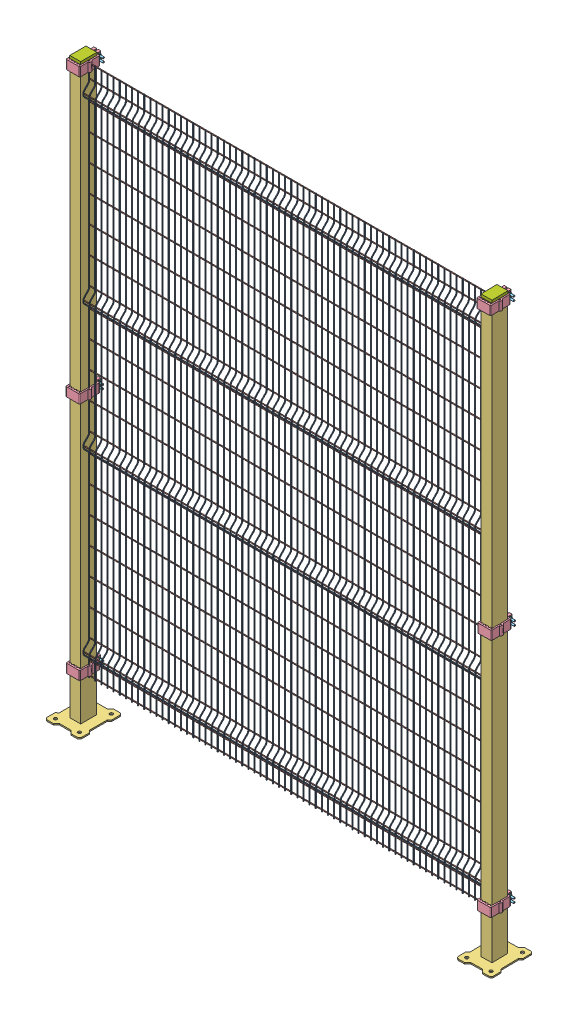
SolidWorks assembly conjunto malha 20x100, configuration Valor predeterminado. Lengths in mm.
Overall size (1674.09 2165.88 162.39).
151 component instances, 7 part files, 62 mates.
Components (placement in the parent):
- Painel Lync Pro 1500 x 2000 step-1: Painel Lync Pro 1500 x 2000 step [Valor predeterminado] at (1050.3689 171.7839 2000) size (1500 2000 28)
  - Painel Lync Pro 1500 x 2000 step.STEP-1: Painel Lync Pro 1500 x 2000 step.STEP [Valor predeterminado] at origin size (1500 2000 28)
    - Arame vertical.STEP-1: Arame vertical.STEP [Valor predeterminado] at (-259.8823 -1220.0686 1996) size (3 2000 25)
    - Arame vertical.STEP-2: Arame vertical.STEP [Valor predeterminado] at (-282.8823 -1220.0686 1996) size (3 2000 25)
    - Arame vertical.STEP-3: Arame vertical.STEP [Valor predeterminado] at (-305.8823 -1220.0686 1996) size (3 2000 25)
    - Arame vertical.STEP-4: Arame vertical.STEP [Valor predeterminado] at (-328.8823 -1220.0686 1996) size (3 2000 25)
    - Arame vertical.STEP-5: Arame vertical.STEP [Valor predeterminado] at (-351.8823 -1220.0686 1996) size (3 2000 25)
    - Arame vertical.STEP-6: Arame vertical.STEP [Valor predeterminado] at (-374.8823 -1220.0686 1996) size (3 2000 25)
    - Arame vertical.STEP-7: Arame vertical.STEP [Valor predeterminado] at (-397.8823 -1220.0686 1996) size (3 2000 25)
    - Arame vertical.STEP-8: Arame vertical.STEP [Valor predeterminado] at (-420.8823 -1220.0686 1996) size (3 2000 25)
    - Arame vertical.STEP-9: Arame vertical.STEP [Valor predeterminado] at (-443.8823 -1220.0686 1996) size (3 2000 25)
    - Arame vertical.STEP-10: Arame vertical.STEP [Valor predeterminado] at (-466.8823 -1220.0686 1996) size (3 2000 25)
    - Arame vertical.STEP-11: Arame vertical.STEP [Valor predeterminado] at (-489.8823 -1220.0686 1996) size (3 2000 25)
    - Arame vertical.STEP-12: Arame vertical.STEP [Valor predeterminado] at (-512.8823 -1220.0686 1996) size (3 2000 25)
    - Arame vertical.STEP-13: Arame vertical.STEP [Valor predeterminado] at (-535.8823 -1220.0686 1996) size (3 2000 25)
    - Arame vertical.STEP-14: Arame vertical.STEP [Valor predeterminado] at (-558.8823 -1220.0686 1996) size (3 2000 25)
    - Arame vertical.STEP-15: Arame vertical.STEP [Valor predeterminado] at (-581.8823 -1220.0686 1996) size (3 2000 25)
    - Arame vertical.STEP-16: Arame vertical.STEP [Valor predeterminado] at (-604.8823 -1220.0686 1996) size (3 2000 25)
    - Arame vertical.STEP-17: Arame vertical.STEP [Valor predeterminado] at (-627.8823 -1220.0686 1996) size (3 2000 25)
    - Arame vertical.STEP-18: Arame vertical.STEP [Valor predeterminado] at (-650.8823 -1220.0686 1996) size (3 2000 25)
    - Arame vertical.STEP-19: Arame vertical.STEP [Valor predeterminado] at (-673.8823 -1220.0686 1996) size (3 2000 25)
    - Arame vertical.STEP-20: Arame vertical.STEP [Valor predeterminado] at (-696.8823 -1220.0686 1996) size (3 2000 25)
    - Arame vertical.STEP-21: Arame vertical.STEP [Valor predeterminado] at (-719.8823 -1220.0686 1996) size (3 2000 25)
    - Arame vertical.STEP-22: Arame vertical.STEP [Valor predeterminado] at (-742.8823 -1220.0686 1996) size (3 2000 25)
    - Arame vertical.STEP-23: Arame vertical.STEP [Valor predeterminado] at (-765.8823 -1220.0686 1996) size (3 2000 25)
    - Arame vertical.STEP-24: Arame vertical.STEP [Valor predeterminado] at (-788.8823 -1220.0686 1996) size (3 2000 25)
    - Arame vertical.STEP-25: Arame vertical.STEP [Valor predeterminado] at (-811.8823 -1220.0686 1996) size (3 2000 25)
    - Arame vertical.STEP-26: Arame vertical.STEP [Valor predeterminado] at (-834.8823 -1220.0686 1996) size (3 2000 25)
    - Arame vertical.STEP-27: Arame vertical.STEP [Valor predeterminado] at (-857.8823 -1220.0686 1996) size (3 2000 25)
    - Arame vertical.STEP-28: Arame vertical.STEP [Valor predeterminado] at (-880.8823 -1220.0686 1996) size (3 2000 25)
    - Arame vertical.STEP-29: Arame vertical.STEP [Valor predeterminado] at (-903.8823 -1220.0686 1996) size (3 2000 25)
    - Arame vertical.STEP-30: Arame vertical.STEP [Valor predeterminado] at (-926.8823 -1220.0686 1996) size (3 2000 25)
    - Arame vertical.STEP-31: Arame vertical.STEP [Valor predeterminado] at (-949.8823 -1220.0686 1996) size (3 2000 25)
    - Arame vertical.STEP-32: Arame vertical.STEP [Valor predeterminado] at (-972.8823 -1220.0686 1996) size (3 2000 25)
    - Arame vertical.STEP-33: Arame vertical.STEP [Valor predeterminado] at (-995.8823 -1220.0686 1996) size (3 2000 25)
    - Arame vertical.STEP-34: Arame vertical.STEP [Valor predeterminado] at (-1018.8823 -1220.0686 1996) size (3 2000 25)
    - Arame vertical.STEP-35: Arame vertical.STEP [Valor predeterminado] at (-1041.8823 -1220.0686 1996) size (3 2000 25)
    - Arame vertical.STEP-36: Arame vertical.STEP [Valor predeterminado] at (-1064.8823 -1220.0686 1996) size (3 2000 25)
    - Arame vertical.STEP-37: Arame vertical.STEP [Valor predeterminado] at (-1087.8823 -1220.0686 1996) size (3 2000 25)
    - Arame vertical.STEP-38: Arame vertical.STEP [Valor predeterminado] at (-1110.8823 -1220.0686 1996) size (3 2000 25)
    - Arame vertical.STEP-39: Arame vertical.STEP [Valor predeterminado] at (-1133.8823 -1220.0686 1996) size (3 2000 25)
    - Arame vertical.STEP-40: Arame vertical.STEP [Valor predeterminado] at (-1156.8823 -1220.0686 1996) size (3 2000 25)
    - Arame vertical.STEP-41: Arame vertical.STEP [Valor predeterminado] at (-1179.8823 -1220.0686 1996) size (3 2000 25)
    - Arame vertical.STEP-42: Arame vertical.STEP [Valor predeterminado] at (-1202.8823 -1220.0686 1996) size (3 2000 25)
    - Arame vertical.STEP-43: Arame vertical.STEP [Valor predeterminado] at (-1225.8823 -1220.0686 1996) size (3 2000 25)
    - Arame vertical.STEP-44: Arame vertical.STEP [Valor predeterminado] at (-1248.8823 -1220.0686 1996) size (3 2000 25)
    - Arame vertical.STEP-45: Arame vertical.STEP [Valor predeterminado] at (-1271.8823 -1220.0686 1996) size (3 2000 25)
    - Arame vertical.STEP-46: Arame vertical.STEP [Valor predeterminado] at (-1294.8823 -1220.0686 1996) size (3 2000 25)
    - Arame vertical.STEP-47: Arame vertical.STEP [Valor predeterminado] at (-1317.8823 -1220.0686 1996) size (3 2000 25)
    - Arame vertical.STEP-48: Arame vertical.STEP [Valor predeterminado] at (-1340.8823 -1220.0686 1996) size (3 2000 25)
    - Arame vertical.STEP-49: Arame vertical.STEP [Valor predeterminado] at (-1363.8823 -1220.0686 1996) size (3 2000 25)
    - Arame vertical.STEP-50: Arame vertical.STEP [Valor predeterminado] at (-1386.8823 -1220.0686 1996) size (3 2000 25)
    - Arame vertical.STEP-51: Arame vertical.STEP [Valor predeterminado] at (-1409.8823 -1220.0686 1996) size (3 2000 25)
    - Arame vertical.STEP-52: Arame vertical.STEP [Valor predeterminado] at (-1432.8823 -1220.0686 1996) size (3 2000 25)
    - Arame vertical.STEP-53: Arame vertical.STEP [Valor predeterminado] at (-1455.8823 -1220.0686 1996) size (3 2000 25)
    - Arame vertical.STEP-54: Arame vertical.STEP [Valor predeterminado] at (-1478.8823 -1220.0686 1996) size (3 2000 25)
    - Arame vertical.STEP-55: Arame vertical.STEP [Valor predeterminado] at (-1501.8823 -1220.0686 1996) size (3 2000 25)
    - Arame vertical.STEP-56: Arame vertical.STEP [Valor predeterminado] at (-1524.8823 -1220.0686 1996) size (3 2000 25)
    - Arame vertical.STEP-57: Arame vertical.STEP [Valor predeterminado] at (-1547.8823 -1220.0686 1996) size (3 2000 25)
    - Arame vertical.STEP-58: Arame vertical.STEP [Valor predeterminado] at (-1570.8823 -1220.0686 1996) size (3 2000 25)
    - Arame vertical.STEP-59: Arame vertical.STEP [Valor predeterminado] at (-1593.8823 -1220.0686 1996) size (3 2000 25)
    - Arame vertical.STEP-60: Arame vertical.STEP [Valor predeterminado] at (-1616.8823 -1220.0686 1996) size (3 2000 25)
    - Arame vertical.STEP-61: Arame vertical.STEP [Valor predeterminado] at (-1639.8823 -1220.0686 1996) size (3 2000 25)
    - Arame vertical.STEP-62: Arame vertical.STEP [Valor predeterminado] at (-1662.8823 -1220.0686 1996) size (3 2000 25)
    - Arame vertical.STEP-63: Arame vertical.STEP [Valor predeterminado] at (-1685.8823 -1220.0686 1996) size (3 2000 25)
    - Arame vertical.STEP-64: Arame vertical.STEP [Valor predeterminado] at (-1708.8823 -1220.0686 1996) size (3 2000 25)
    - Arame vertical.STEP-65: Arame vertical.STEP [Valor predeterminado] at (-1731.8823 -1220.0686 1996) size (3 2000 25)
    - Arame horizontal.STEP-1: Arame horizontal.STEP [Valor predeterminado] at (-258.3823 -1128.0686 2015) size (1500 3 3)
    - Arame vertical.STEP-66: Arame vertical.STEP [Valor predeterminado] at (-1754.8823 -1220.0686 1996) size (3 2000 25)
    - Arame horizontal.STEP-2: Arame horizontal.STEP [Valor predeterminado] at (-258.3823 -458.0686 2015) size (1500 3 3)
    - Arame horizontal.STEP-3: Arame horizontal.STEP [Valor predeterminado] at (-258.3823 14.9314 2015) size (1500 3 3)
    - Arame horizontal.STEP-4: Arame horizontal.STEP [Valor predeterminado] at (-258.3823 687.9314 2015) size (1500 3 3)
    - Arame horizontal.STEP-5: Arame horizontal.STEP [Valor predeterminado] at (-258.3823 -1165.5686 1993) size (1500 3 3)
    - Arame horizontal.STEP-6: Arame horizontal.STEP [Valor predeterminado] at (-258.3823 -1215.5686 1993) size (1500 3 3)
    - Arame horizontal.STEP-7: Arame horizontal.STEP [Valor predeterminado] at (-258.3823 775.4314 1993) size (1500 3 3)
    - Arame horizontal.STEP-8: Arame horizontal.STEP [Valor predeterminado] at (-258.3823 725.4314 1993) size (1500 3 3)
    - Arame horizontal.STEP-9: Arame horizontal.STEP [Valor predeterminado] at (-258.3823 -793.0686 1993) size (1500 3 3)
    - Arame horizontal.STEP-10: Arame horizontal.STEP [Valor predeterminado] at (-258.3823 -693.0686 1993) size (1500 3 3)
    - Arame horizontal.STEP-11: Arame horizontal.STEP [Valor predeterminado] at (-258.3823 -593.0686 1993) size (1500 3 3)
    - Arame horizontal.STEP-12: Arame horizontal.STEP [Valor predeterminado] at (-258.3823 -493.0686 1993) size (1500 3 3)
    - Arame horizontal.STEP-13: Arame horizontal.STEP [Valor predeterminado] at (-258.3823 -893.0686 1993) size (1500 3 3)
    - Arame horizontal.STEP-14: Arame horizontal.STEP [Valor predeterminado] at (-258.3823 -993.0686 1993) size (1500 3 3)
    - Arame horizontal.STEP-15: Arame horizontal.STEP [Valor predeterminado] at (-258.3823 -1093.0686 1993) size (1500 3 3)
    - Arame horizontal.STEP-16: Arame horizontal.STEP [Valor predeterminado] at (-258.3823 -793.0686 1993) size (1500 3 3)
    - Arame horizontal.STEP-17: Arame horizontal.STEP [Valor predeterminado] at (-258.3823 -893.0686 1993) size (1500 3 3)
    - Arame horizontal.STEP-18: Arame horizontal.STEP [Valor predeterminado] at (-258.3823 -993.0686 1993) size (1500 3 3)
    - Arame horizontal.STEP-19: Arame horizontal.STEP [Valor predeterminado] at (-258.3823 -693.0686 1993) size (1500 3 3)
    - Arame horizontal.STEP-20: Arame horizontal.STEP [Valor predeterminado] at (-258.3823 -793.0686 1993) size (1500 3 3)
    - Arame horizontal.STEP-21: Arame horizontal.STEP [Valor predeterminado] at (-258.3823 -893.0686 1993) size (1500 3 3)
    - Arame horizontal.STEP-22: Arame horizontal.STEP [Valor predeterminado] at (-258.3823 -593.0686 1993) size (1500 3 3)
    - Arame horizontal.STEP-23: Arame horizontal.STEP [Valor predeterminado] at (-258.3823 -693.0686 1993) size (1500 3 3)
    - Arame horizontal.STEP-24: Arame horizontal.STEP [Valor predeterminado] at (-258.3823 -793.0686 1993) size (1500 3 3)
    - Arame horizontal.STEP-25: Arame horizontal.STEP [Valor predeterminado] at (-258.3823 351.4314 1993) size (1500 3 3)
    - Arame horizontal.STEP-26: Arame horizontal.STEP [Valor predeterminado] at (-258.3823 251.4314 1993) size (1500 3 3)
    - Arame horizontal.STEP-27: Arame horizontal.STEP [Valor predeterminado] at (-258.3823 151.4314 1993) size (1500 3 3)
    - Arame horizontal.STEP-28: Arame horizontal.STEP [Valor predeterminado] at (-258.3823 51.4314 1993) size (1500 3 3)
    - Arame horizontal.STEP-29: Arame horizontal.STEP [Valor predeterminado] at (-258.3823 451.4314 1993) size (1500 3 3)
    - Arame horizontal.STEP-30: Arame horizontal.STEP [Valor predeterminado] at (-258.3823 351.4314 1993) size (1500 3 3)
    - Arame horizontal.STEP-31: Arame horizontal.STEP [Valor predeterminado] at (-258.3823 251.4314 1993) size (1500 3 3)
    - Arame horizontal.STEP-32: Arame horizontal.STEP [Valor predeterminado] at (-258.3823 151.4314 1993) size (1500 3 3)
    - Arame horizontal.STEP-33: Arame horizontal.STEP [Valor predeterminado] at (-258.3823 551.4314 1993) size (1500 3 3)
    - Arame horizontal.STEP-34: Arame horizontal.STEP [Valor predeterminado] at (-258.3823 451.4314 1993) size (1500 3 3)
    - Arame horizontal.STEP-35: Arame horizontal.STEP [Valor predeterminado] at (-258.3823 351.4314 1993) size (1500 3 3)
    - Arame horizontal.STEP-36: Arame horizontal.STEP [Valor predeterminado] at (-258.3823 251.4314 1993) size (1500 3 3)
    - Arame horizontal.STEP-37: Arame horizontal.STEP [Valor predeterminado] at (-258.3823 651.4314 1993) size (1500 3 3)
    - Arame horizontal.STEP-38: Arame horizontal.STEP [Valor predeterminado] at (-258.3823 551.4314 1993) size (1500 3 3)
    - Arame horizontal.STEP-39: Arame horizontal.STEP [Valor predeterminado] at (-258.3823 451.4314 1993) size (1500 3 3)
    - Arame horizontal.STEP-40: Arame horizontal.STEP [Valor predeterminado] at (-258.3823 351.4314 1993) size (1500 3 3)
    - Arame horizontal.STEP-41: Arame horizontal.STEP [Valor predeterminado] at (-258.3823 -221.5686 1993) size (1500 3 3)
    - Arame horizontal.STEP-42: Arame horizontal.STEP [Valor predeterminado] at (-258.3823 -321.5686 1993) size (1500 3 3)
    - Arame horizontal.STEP-43: Arame horizontal.STEP [Valor predeterminado] at (-258.3823 -421.5686 1993) size (1500 3 3)
    - Arame horizontal.STEP-44: Arame horizontal.STEP [Valor predeterminado] at (-258.3823 -121.5686 1993) size (1500 3 3)
    - Arame horizontal.STEP-45: Arame horizontal.STEP [Valor predeterminado] at (-258.3823 -221.5686 1993) size (1500 3 3)
    - Arame horizontal.STEP-46: Arame horizontal.STEP [Valor predeterminado] at (-258.3823 -321.5686 1993) size (1500 3 3)
    - Arame horizontal.STEP-47: Arame horizontal.STEP [Valor predeterminado] at (-258.3823 -21.5686 1993) size (1500 3 3)
    - Arame horizontal.STEP-48: Arame horizontal.STEP [Valor predeterminado] at (-258.3823 -121.5686 1993) size (1500 3 3)
    - Arame horizontal.STEP-49: Arame horizontal.STEP [Valor predeterminado] at (-258.3823 -221.5686 1993) size (1500 3 3)
- Poste 60 x 40 x 2150 mm-1: Poste 60 x 40 x 2150 mm [Valor predeterminado] at (750.8183 -1193.3606 4073.483) x (0.999857 0 -0.016899) z (0.016899 0 0.999857) size (130 2150 160)
- Poste 60 x 40 x 2150 mm-2: Poste 60 x 40 x 2150 mm [Valor predeterminado] at (-793.2854 -1187.4853 4073.7015) size (130 2150 160)
- Abracadeira PL 60 x 40 Step-1: Abracadeira PL 60 x 40 Step [Valor predeterminado] at (813.6833 951.6394 3995.6079) x (0.999857 0 -0.016899) z (-0.016899 0 -0.999857) size (61.2 33.4 92.2)
- Abracadeira PL 60 x 40 Step-2: Abracadeira PL 60 x 40 Step [Valor predeterminado] at (-727.7133 957.5147 3996) x (1 0 0) z (0 0 -1) size (61.2 33.4 92.2)
- Abracadeira PL 60 x 40 Step-5: Abracadeira PL 60 x 40 Step [Valor predeterminado] at (815.0561 -104.7674 3993.9845) x (0.999857 0 -0.016899) z (-0.016899 0 -0.999857) size (61.2 33.4 92.2)
- Abracadeira PL 60 x 40 Step-6: Abracadeira PL 60 x 40 Step [Valor predeterminado] at (813.6681 -1006.5868 3994.7081) x (0.999857 0 -0.016899) z (-0.016899 0 -0.999857) size (61.2 33.4 92.2)
- Abracadeira PL 60 x 40 Step-7: Abracadeira PL 60 x 40 Step [Valor predeterminado] at (-727.7133 -1006.2298 3996) x (1 0 0) z (0 0 -1) size (61.2 33.4 92.2)
- Abracadeira PL 60 x 40 Step-8: Abracadeira PL 60 x 40 Step [Valor predeterminado] at (-727.7133 -106.0788 3996.9) x (1 0 0) z (0 0 -1) size (61.2 33.4 92.2)
- 622016x35-1: 622016x35 [Default] at (-731.1133 947.9647 3949.8) size (41 10 10)
- 622016x35-2: 622016x35 [Default] at (-732.8335 -115.6288 3950.7) x (1 0 0) z (0 -0.107 0.994259) size (41 10 10)
- 622016x35-3: 622016x35 [Default] at (-733.2149 -129.9288 3950.7) x (1 0 0) z (0 0.395761 0.918353) size (41 10 10)
- 622016x35-4: 622016x35 [Default] at (-733.0697 -1015.7798 3949.8) x (1 0 0) z (0 0.101251 0.994861) size (41 10 10)
- 622016x35-5: 622016x35 [Default] at (-731.1133 933.6647 3949.8) size (41 10 10)
- 622016x35-7: 622016x35 [Default] at (810.8759 -128.6174 3947.8486) x (0.999857 0 -0.016899) z (0.016899 0 0.999857) size (41 10 10)
- 622016x35-8: 622016x35 [Default] at (809.4879 -1030.4368 3948.5721) x (0.999857 0 -0.016899) z (0.016899 0 0.999857) size (41 10 10)
- 622016x35-9: 622016x35 [Default] at (809.5031 927.7894 3949.472) x (0.999857 0 -0.016899) z (0.016899 0 0.999857) size (41 10 10)
- 622016x35-10: 622016x35 [Default] at (810.8759 -114.3174 3947.8486) x (0.999857 0 -0.016899) z (0.016899 0 0.999857) size (41 10 10)
- 622016x35-11: 622016x35 [Default] at (809.4879 -1016.1368 3948.5721) x (0.999857 0 -0.016899) z (0.016899 0 0.999857) size (41 10 10)
- 622016x35-12: 622016x35 [Default] at (809.5031 942.0894 3949.472) x (0.999857 0 -0.016899) z (0.016899 0 0.999857) size (41 10 10)
- 622016x35-13: 622016x35 [Default] at (-733.2164 -1030.0798 3949.8) x (1 0 0) z (0 0.823855 0.566801) size (41 10 10)
- nut_din934_m6-6-1: nut_din934_m6-6 [Default] at (-709.6133 947.9647 3949.8) x (0 0 -1) z (-1 0 0) size (11.55 10 5.26)
- nut_din934_m6-6-2: nut_din934_m6-6 [Default] at (-709.6133 933.7103 3949.7322) x (0 0 -1) z (-1 0 0) size (11.55 10 5.26)
- nut_din934_m6-6-3: nut_din934_m6-6 [Default] at (-709.6133 -129.9288 3950.7) x (0 0 -1) z (-1 0 0) size (11.55 10 5.26)
- nut_din934_m6-6-4: nut_din934_m6-6 [Default] at (-709.6133 -1030.0798 3949.8) x (0 0 -1) z (-1 0 0) size (11.55 10 5.26)
- nut_din934_m6-6-5: nut_din934_m6-6 [Default] at (-709.6133 -1015.7798 3949.8) x (0 0 -1) z (-1 0 0) size (11.55 10 5.26)
- nut_din934_m6-6-6: nut_din934_m6-6 [Default] at (-709.6133 -115.6288 3950.7) x (0 0 -1) z (-1 0 0) size (11.55 10 5.26)
- nut_din934_m6-6-7: nut_din934_m6-6 [Default] at (830.9848 -1030.4368 3948.2088) x (-0.016899 0 -0.999857) z (-0.999857 0 0.016899) size (11.55 10 5.26)
- nut_din934_m6-6-8: nut_din934_m6-6 [Default] at (830.9848 -1016.1368 3948.2088) x (-0.016899 0 -0.999857) z (-0.999857 0 0.016899) size (11.55 10 5.26)
- nut_din934_m6-6-9: nut_din934_m6-6 [Default] at (832.3728 -128.6174 3947.4852) x (-0.016899 0 -0.999857) z (-0.999857 0 0.016899) size (11.55 10 5.26)
- nut_din934_m6-6-10: nut_din934_m6-6 [Default] at (832.3728 -114.3174 3947.4852) x (-0.016899 0 -0.999857) z (-0.999857 0 0.016899) size (11.55 10 5.26)
- nut_din934_m6-6-11: nut_din934_m6-6 [Default] at (831 927.7894 3949.1087) x (-0.016899 0 -0.999857) z (-0.999857 0 0.016899) size (11.55 10 5.26)
- nut_din934_m6-6-12: nut_din934_m6-6 [Default] at (831 942.0894 3949.1087) x (-0.016899 0 -0.999857) z (-0.999857 0 0.016899) size (11.55 10 5.26)
- TAMPA PLÁSTICA-1: TAMPA PLÁSTICA [Valor predeterminado] at (813.8275 961.6394 3992.305) x (0.016899 0 0.999857) z (0.999857 0 -0.016899) size (61 10 41)
- TAMPA PLÁSTICA-2: TAMPA PLÁSTICA [Valor predeterminado] at (-727.9133 967.5147 3994.6) x (0 0 1) z (1 0 0) size (61 10 41)
Mates (geometry in assembly coordinates):
- Coincidente1: coincident anti-aligned: plane of Poste 60 x 40 x 2150 mm-1 through (833.8261 951.6394 3962.4628) normal (0.999857 0 -0.016899); plane of Abracadeira PL 60 x 40 Step-1 through (834.4336 918.2394 3998.4049) normal (-0.999857 0 0.016899)
- Coincidente2: coincident anti-aligned: plane of Poste 60 x 40 x 2150 mm-1 through (793.8318 951.6394 3963.1388) normal (-0.016899 0 -0.999857); plane of Abracadeira PL 60 x 40 Step-1 through (792.432 918.2394 3963.1624) normal (0.016899 0 0.999857)
- Coincidente3: coincident: line of Poste 60 x 40 x 2150 mm-1 through (793.8318 951.6394 3963.1388) axis (0.999857 0 -0.016899); plane of Abracadeira PL 60 x 40 Step-1 through (791.9333 951.6394 3992.8279) normal (0 1 0)
- Concêntrico1: concentric aligned: cylinder of Painel Lync Pro 1500 x 2000 step-1/Painel Lync Pro 1500 x 2000 step.STEP-1/Arame vertical.STEP-1 through (790.4867 895.3844 3996) axis (0 1 0) radius 1.5; cylinder of Abracadeira PL 60 x 40 Step-1 through (790.4867 918.2394 3996) axis (0 1 0) radius 2.25
- Coincidente5: coincident anti-aligned: plane of Poste 60 x 40 x 2150 mm-1 through (793.8318 951.6394 3963.1388) normal (-0.999857 0 0.016899); plane of Abracadeira PL 60 x 40 Step-5 through (793.8048 -138.1674 3961.539) normal (0.999857 0 -0.016899)
- Tangente1: tangent anti-aligned: plane of Poste 60 x 40 x 2150 mm-1 through (794.8457 951.6394 4023.1302) normal (0.016899 0 0.999857); cylinder of Abracadeira PL 60 x 40 Step-5 through (825.5752 -93.718 4024.6111) axis (0 -1 0) radius 2
- Tangente3: tangent anti-aligned: plane of Poste 60 x 40 x 2150 mm-1 through (794.8457 951.6394 4023.1302) normal (0.016899 0 0.999857); cylinder of Abracadeira PL 60 x 40 Step-6 through (819.1761 -995.5374 4024.7193) axis (0 -1 0) radius 2
- Coincidente6: coincident anti-aligned: plane of Poste 60 x 40 x 2150 mm-1 through (833.8261 951.6394 3962.4628) normal (0.999857 0 -0.016899); plane of Abracadeira PL 60 x 40 Step-6 through (833.8109 -1039.9868 3961.563) normal (-0.999857 0 0.016899)
- Tangente4: tangent anti-aligned: plane of Poste 60 x 40 x 2150 mm-2 through (-748.4133 957.5147 4024.1) normal (0 0 1); cylinder of Abracadeira PL 60 x 40 Step-2 through (-732.7133 968.5641 4026.1) axis (0 -1 0) radius 2
- Coincidente11: coincident aligned: line of Poste 60 x 40 x 2150 mm-2 through (-748.4133 957.5147 3964.1) axis (0 0 1); line of Abracadeira PL 60 x 40 Step-2 through (-748.4133 957.5147 4003) axis (0 0 1)
- Concêntrico2: concentric aligned: cylinder of Painel Lync Pro 1500 x 2000 step-1/Painel Lync Pro 1500 x 2000 step.STEP-1/Arame vertical.STEP-66 through (-704.5133 895.3844 3996) axis (0 1 0) radius 1.5; cylinder of Abracadeira PL 60 x 40 Step-2 through (-704.5133 924.1147 3996) axis (0 1 0) radius 2.25
- Concêntrico3: concentric aligned: circle of Painel Lync Pro 1500 x 2000 step-1/Painel Lync Pro 1500 x 2000 step.STEP-1/Arame vertical.STEP-66; circle of Abracadeira PL 60 x 40 Step-2
- Coincidente12: coincident anti-aligned: plane of Poste 60 x 40 x 2150 mm-2 through (-748.4133 957.5147 3964.1) normal (-1 0 0); plane of Abracadeira PL 60 x 40 Step-8 through (-748.4133 -139.4788 3964.1) normal (1 0 0)
- Coincidente13: coincident anti-aligned: plane of Poste 60 x 40 x 2150 mm-2 through (-748.4133 957.5147 3964.1) normal (0 0 -1); plane of Abracadeira PL 60 x 40 Step-8 through (-748.4133 -139.4788 3964.1) normal (0 0 1)
- Paralelo1: parallel anti-aligned: plane of Painel Lync Pro 1500 x 2000 step-1/Painel Lync Pro 1500 x 2000 step.STEP-1/Arame horizontal.STEP-6 through (-708.0133 -1043.7847 3993) normal (-1 0 0); plane of Poste 60 x 40 x 2150 mm-2 through (-708.4133 957.5147 3964.1) normal (1 0 0)
- Concêntrico8: concentric aligned: cylinder of Painel Lync Pro 1500 x 2000 step-1/Painel Lync Pro 1500 x 2000 step.STEP-1/Arame vertical.STEP-66 through (-704.5133 -1048.2847 3996) axis (0 1 0) radius 1.5; cylinder of Abracadeira PL 60 x 40 Step-7 through (-704.5133 -1039.6298 3996) axis (0 1 0) radius 2.25
- Coincidente21: coincident anti-aligned: plane of Abracadeira PL 60 x 40 Step-2 through (-731.1133 947.9647 3949.8) normal (-1 0 0); circle of 622016x35-1
- Concêntrico9: concentric aligned: circle of Abracadeira PL 60 x 40 Step-2; circle of 622016x35-1
- Concêntrico10: concentric anti-aligned: circle of Abracadeira PL 60 x 40 Step-2; cylinder of 622016x35-5 through (-693.1133 933.6647 3949.8) axis (1 0 0) radius 5
- Coincidente22: coincident anti-aligned: plane of Abracadeira PL 60 x 40 Step-2 through (-731.1133 933.6647 3949.8) normal (-1 0 0); plane of 622016x35-5 through (-731.1133 933.6647 3944.8) normal (1 0 0)
- Concêntrico11: concentric anti-aligned: circle of Abracadeira PL 60 x 40 Step-8; cylinder of 622016x35-2 through (-694.8335 -115.6288 3950.7) axis (1 0 0) radius 5
- Concêntrico13: concentric aligned: cylinder of Abracadeira PL 60 x 40 Step-8 through (-748.8133 -129.9288 3950.7) axis (1 0 0) radius 5.8; cylinder of 622016x35-3 through (-695.2149 -129.9288 3950.7) axis (1 0 0) radius 5
- Concêntrico14: concentric anti-aligned: circle of Abracadeira PL 60 x 40 Step-7; cylinder of 622016x35-4 through (-695.0697 -1015.7798 3949.8) axis (1 0 0) radius 5
- Concêntrico17: concentric anti-aligned: circle of Abracadeira PL 60 x 40 Step-7; cylinder of 622016x35-13 through (-695.2164 -1030.0798 3949.8) axis (1 0 0) radius 5
- Concêntrico18: concentric aligned: circle of Abracadeira PL 60 x 40 Step-1; circle of 622016x35-12
- Coincidente23: coincident anti-aligned: plane of Abracadeira PL 60 x 40 Step-1 through (809.5031 942.0894 3949.472) normal (-0.999857 0 0.016899); plane of 622016x35-12 through (809.4186 942.0894 3944.4727) normal (0.999857 0 -0.016899)
- Concêntrico19: concentric anti-aligned: circle of Abracadeira PL 60 x 40 Step-1; circle of 622016x35-9
- Coincidente25: coincident anti-aligned: plane of Abracadeira PL 60 x 40 Step-1 through (809.5031 927.7894 3949.472) normal (-0.999857 0 0.016899); plane of 622016x35-9 through (809.4186 927.7894 3944.4727) normal (0.999857 0 -0.016899)
- Concêntrico20: concentric aligned: circle of Abracadeira PL 60 x 40 Step-5; circle of 622016x35-10
- Coincidente26: coincident anti-aligned: plane of Abracadeira PL 60 x 40 Step-5 through (810.8759 -114.3174 3947.8486) normal (-0.999857 0 0.016899); plane of 622016x35-10 through (810.7914 -114.3174 3942.8493) normal (0.999857 0 -0.016899)
- Concêntrico21: concentric anti-aligned: circle of Abracadeira PL 60 x 40 Step-5; circle of 622016x35-7
- Coincidente27: coincident anti-aligned: plane of Abracadeira PL 60 x 40 Step-5 through (810.8759 -128.6174 3947.8486) normal (-0.999857 0 0.016899); plane of 622016x35-7 through (810.7914 -128.6174 3942.8493) normal (0.999857 0 -0.016899)
- Concêntrico22: concentric aligned: circle of Abracadeira PL 60 x 40 Step-6; circle of 622016x35-11
- Coincidente28: coincident anti-aligned: plane of Abracadeira PL 60 x 40 Step-6 through (809.4879 -1016.1368 3948.5721) normal (-0.999857 0 0.016899); plane of 622016x35-11 through (809.4034 -1016.1368 3943.5728) normal (0.999857 0 -0.016899)
- Concêntrico23: concentric anti-aligned: circle of Abracadeira PL 60 x 40 Step-6; circle of 622016x35-8
- Coincidente29: coincident anti-aligned: plane of Abracadeira PL 60 x 40 Step-6 through (809.4879 -1030.4368 3948.5721) normal (-0.999857 0 0.016899); plane of 622016x35-8 through (809.4034 -1030.4368 3943.5728) normal (0.999857 0 -0.016899)
- Concêntrico25: concentric anti-aligned: circle of 622016x35-12; circle of nut_din934_m6-6-12
- Coincidente32: coincident anti-aligned: plane of Abracadeira PL 60 x 40 Step-1 through (825.8656 918.2394 3941.1943) normal (0.999857 0 -0.016899); plane of nut_din934_m6-6-12 through (826.0007 942.0894 3949.1932) normal (-0.999857 0 0.016899)
- Concêntrico26: concentric anti-aligned: circle of 622016x35-9; circle of nut_din934_m6-6-11
- Coincidente33: coincident anti-aligned: plane of Abracadeira PL 60 x 40 Step-1 through (825.8656 918.2394 3941.1943) normal (0.999857 0 -0.016899); plane of nut_din934_m6-6-11 through (826.0007 927.7894 3949.1932) normal (-0.999857 0 0.016899)
- Concêntrico27: concentric anti-aligned: circle of 622016x35-10; circle of nut_din934_m6-6-10
- Coincidente34: coincident aligned: plane of Abracadeira PL 60 x 40 Step-5 through (827.2383 -138.1674 3939.5709) normal (0.999857 0 -0.016899); circle of nut_din934_m6-6-10
- Concêntrico28: concentric anti-aligned: circle of 622016x35-7; circle of nut_din934_m6-6-9
- Coincidente35: coincident anti-aligned: plane of Abracadeira PL 60 x 40 Step-5 through (827.2383 -138.1674 3939.5709) normal (0.999857 0 -0.016899); plane of nut_din934_m6-6-9 through (827.3735 -128.6174 3947.5697) normal (-0.999857 0 0.016899)
- Coincidente43: coincident anti-aligned: plane of Abracadeira PL 60 x 40 Step-6 through (825.8504 -1039.9868 3940.2944) normal (0.999857 0 -0.016899); plane of nut_din934_m6-6-8 through (825.9855 -1016.1368 3948.2933) normal (-0.999857 0 0.016899)
- Concêntrico30: concentric anti-aligned: circle of 622016x35-8; circle of nut_din934_m6-6-7
- Coincidente44: coincident anti-aligned: plane of Abracadeira PL 60 x 40 Step-6 through (825.8504 -1039.9868 3940.2944) normal (0.999857 0 -0.016899); plane of nut_din934_m6-6-7 through (825.9855 -1030.4368 3948.2933) normal (-0.999857 0 0.016899)
- Concêntrico31: concentric aligned: cone of 622016x35-1; cone of nut_din934_m6-6-1 through (-714.3427 947.9647 3949.8) axis (1 0 0)
- Coincidente45: coincident anti-aligned: plane of Abracadeira PL 60 x 40 Step-2 through (-714.6133 924.1147 3941.8) normal (1 0 0); plane of nut_din934_m6-6-1 through (-714.6133 947.9647 3949.8) normal (-1 0 0)
- Coincidente50: coincident anti-aligned: plane of Abracadeira PL 60 x 40 Step-2 through (-714.6133 924.1147 3941.8) normal (1 0 0); plane of nut_din934_m6-6-2 through (-714.6133 933.7103 3949.7322) normal (-1 0 0)
- Concêntrico32: concentric anti-aligned: circle of 622016x35-2; circle of nut_din934_m6-6-6
- Coincidente51: coincident anti-aligned: plane of Abracadeira PL 60 x 40 Step-8 through (-714.6133 -139.4788 3942.7) normal (1 0 0); plane of nut_din934_m6-6-6 through (-714.6133 -115.6288 3950.7) normal (-1 0 0)
- Concêntrico33: concentric anti-aligned: circle of 622016x35-3; circle of nut_din934_m6-6-3
- Coincidente52: coincident anti-aligned: plane of Abracadeira PL 60 x 40 Step-8 through (-714.6133 -139.4788 3942.7) normal (1 0 0); plane of nut_din934_m6-6-3 through (-714.6133 -129.9288 3950.7) normal (-1 0 0)
- Concêntrico34: concentric anti-aligned: circle of 622016x35-4; circle of nut_din934_m6-6-5
- Coincidente53: coincident anti-aligned: plane of Abracadeira PL 60 x 40 Step-7 through (-714.6133 -1039.6298 3941.8) normal (1 0 0); plane of nut_din934_m6-6-5 through (-714.6133 -1015.7798 3949.8) normal (-1 0 0)
- Concêntrico35: concentric anti-aligned: circle of 622016x35-13; circle of nut_din934_m6-6-4
- Coincidente54: coincident anti-aligned: plane of Abracadeira PL 60 x 40 Step-7 through (-714.6133 -1039.6298 3941.8) normal (1 0 0); plane of nut_din934_m6-6-4 through (-714.6133 -1030.0798 3949.8) normal (-1 0 0)
- Coincidente55: coincident aligned: line of Poste 60 x 40 x 2150 mm-1 through (833.8261 951.6394 3962.4628) axis (0.016899 0 0.999857); line of TAMPA PLÁSTICA-1 through (833.8092 951.6394 3961.463) axis (0.016899 0 0.999857)
- Coincidente56: coincident aligned: line of Poste 60 x 40 x 2150 mm-1 through (794.8457 951.6394 4023.1302) axis (0.999857 0 -0.016899); line of TAMPA PLÁSTICA-1 through (793.8459 951.6394 4023.1471) axis (0.999857 0 -0.016899)
- Coincidente57: coincident aligned: line of Poste 60 x 40 x 2150 mm-2 through (-748.4133 957.5147 3964.1) axis (1 0 0); line of TAMPA PLÁSTICA-2 through (-743.0116 957.5599 3972.9514) axis (1 0 0)
- Coincidente58: coincident aligned: line of Abracadeira PL 60 x 40 Step-2 through (-748.4133 957.5147 3980.6) axis (0 0 1); line of TAMPA PLÁSTICA-2 through (-748.4133 957.5147 3964.1) axis (0 0 1)
